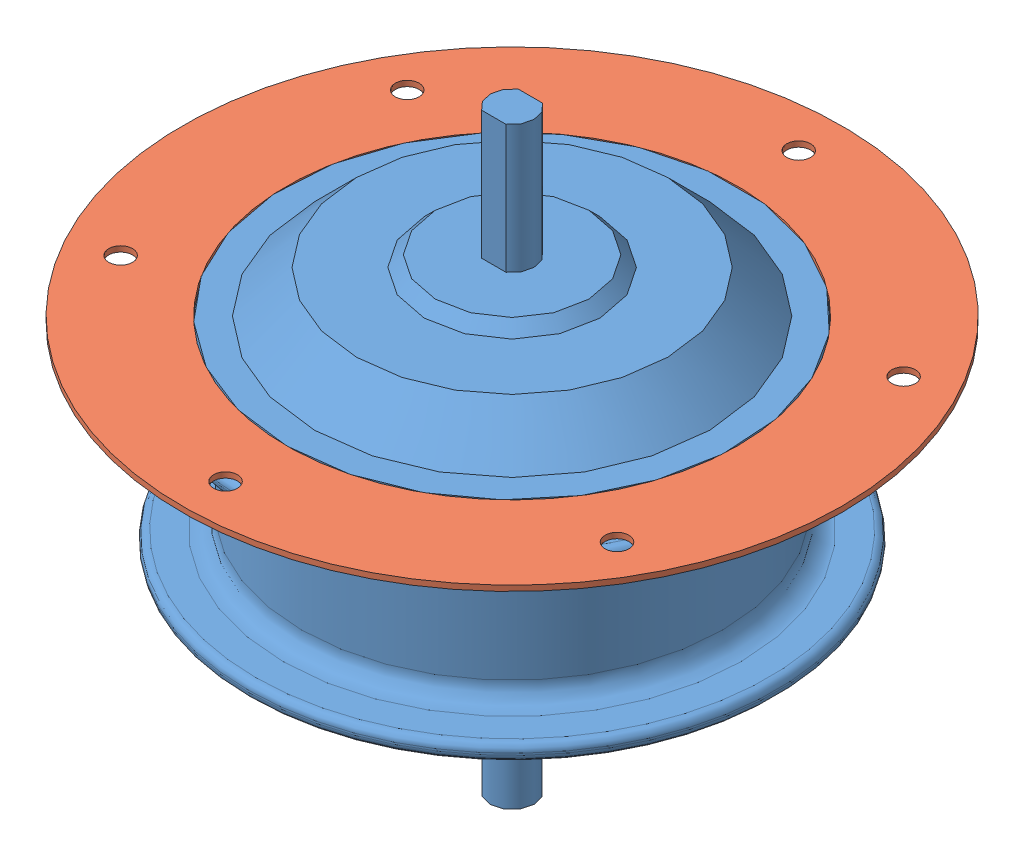
SolidWorks assembly Сборка2, configuration По умолчанию. Lengths in mm.
Overall size (180 162 180).
2 component instances, 2 part files, 4 mates.
Components (placement in the parent):
- dq100-1: dq100 [По умолчанию] at origin size (144 162 144)
- Деталь8^Сборка2-1: Деталь8^Сборка2 [По умолчанию] at (0 30.5 0) x (1 0 0) z (0 1 0) size (180 180 1.5) (virtual)
Mates (geometry in assembly coordinates):
- На месте1: in place: plane of dq100-1 through (0 30.5 54) normal (0 1 0); plane of Деталь8^Сборка2-1 through (0 30.5 0) normal (0 1 0); moOrthogonalPlaneRef_w of dq100-1 through (0 30.5 54) normal (0 1 0); plane of Деталь8^Сборка2-1 through (0 30.5 0) normal (0 0 -1); plane of dq100-1 through (0 30.5 54) normal (0 1 0); plane of Деталь8^Сборка2-1 through (0 30.5 0) normal (1 0 0); plane of dq100-1 through (0 30.5 54) normal (0 1 0); unknown of Деталь8^Сборка2-1
- Совпадение1: coincident: plane of dq100-1; plane of ?
- Совпадение2: coincident: moOrthogonalPlaneRef_w of dq100-1 through (0 30.5 0) normal (0 0 -1); plane of Деталь8^Сборка2-1 through (0 30.5 0) normal (0 0 -1)
- Совпадение3: coincident: moOrthogonalPlaneRef_w of dq100-1 through (0 30.5 0) normal (-1 0 0); plane of Деталь8^Сборка2-1 through (0 30.5 0) normal (1 0 0)
